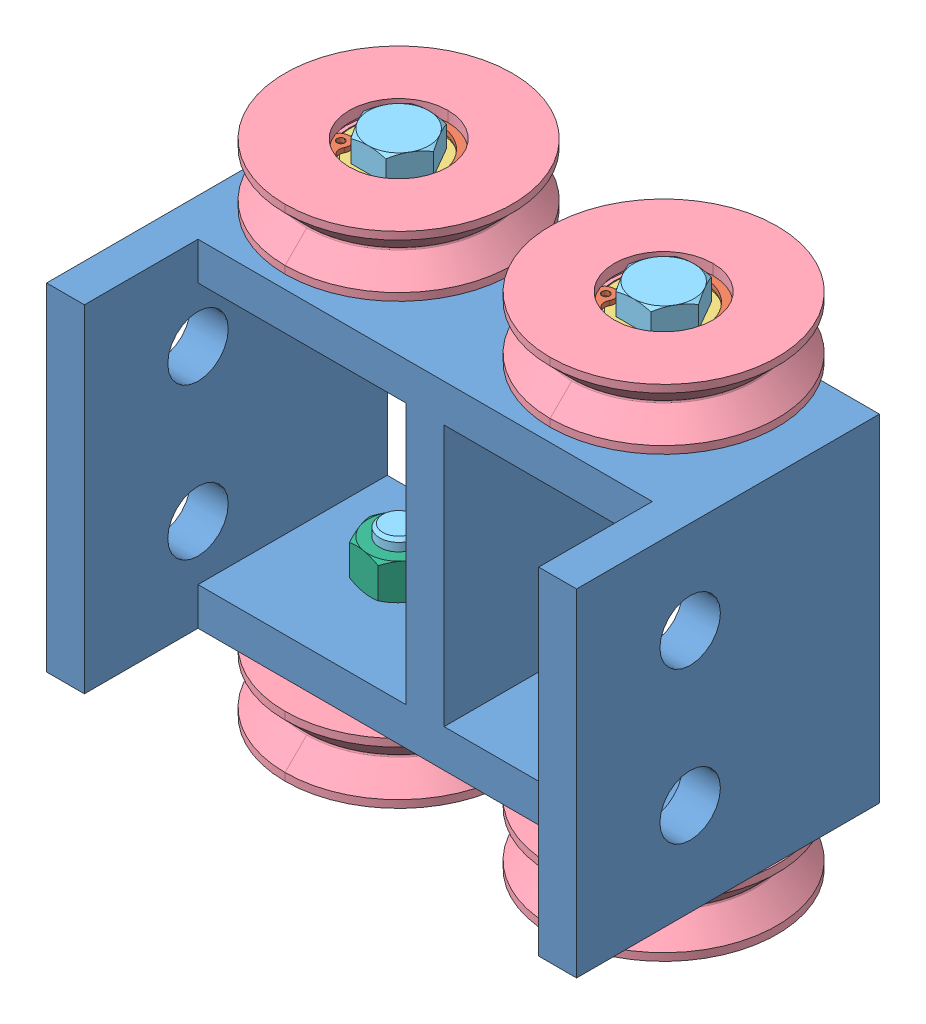
SolidWorks assembly Z_Hub, configuration Default. Lengths in mm.
Overall size (140 136.8 88).
29 component instances, 6 part files, 35 mates.
Components (placement in the parent):
- Z_Internal_Hub-1: Z_Internal_Hub [Default] at (36.1913 98.0055 130.8197) size (140 89 80)
- VMQN60_6-1: VMQN60_6 [Default] at (1.1913 39.5245 152.8197) x (0 1 0) z (0 0 1) size (16 60 60)
  - VMQN60_6_3-1: VMQN60_6_3 [Default] at (-4.6 0 0) size (1.2 26.01 27.2)
  - VMQN60_6_5-1: VMQN60_6_5 [Default] at (4 0 0) x (-1 0 0) z (0 0 1) size (8 26 26)
  - VMQN60_6_7-1: VMQN60_6_7 [Default] at origin size (16 60 60)
- VMQN60_6-2: VMQN60_6 [Default] at (71.1913 155.5245 152.8197) x (0 -1 0) z (0 0 1) size (16 60 60)
  - VMQN60_6_3-1: VMQN60_6_3 [Default] at (-4.6 0 0) size (1.2 26.01 27.2)
  - VMQN60_6_5-1: VMQN60_6_5 [Default] at (4 0 0) x (-1 0 0) z (0 0 1) size (8 26 26)
  - VMQN60_6_7-1: VMQN60_6_7 [Default] at origin size (16 60 60)
- VMQN60_6-3: VMQN60_6 [Default] at (1.1913 155.5245 152.8197) x (0 -1 0) z (0 0 1) size (16 60 60)
  - VMQN60_6_3-1: VMQN60_6_3 [Default] at (-4.6 0 0) size (1.2 26.01 27.2)
  - VMQN60_6_5-1: VMQN60_6_5 [Default] at (4 0 0) x (-1 0 0) z (0 0 1) size (8 26 26)
  - VMQN60_6_7-1: VMQN60_6_7 [Default] at origin size (16 60 60)
- VMQN60_6-4: VMQN60_6 [Default] at (71.1913 39.5245 152.8197) x (0 1 0) z (0 0 1) size (16 60 60)
  - VMQN60_6_3-1: VMQN60_6_3 [Default] at (-4.6 0 0) size (1.2 26.01 27.2)
  - VMQN60_6_5-1: VMQN60_6_5 [Default] at (4 0 0) x (-1 0 0) z (0 0 1) size (8 26 26)
  - VMQN60_6_7-1: VMQN60_6_7 [Default] at origin size (16 60 60)
- hex bolt gradeb_iso-1: hex bolt gradeb_iso [ISO 4015 - M10 x 40 x 40-N] at (71.1913 29.1245 152.8197) x (0 1 0) z (0 0 1) size (46.4 18.48 16)
- hex bolt gradeb_iso-2: hex bolt gradeb_iso [ISO 4015 - M10 x 40 x 40-N] at (1.1913 29.1245 152.8197) x (0 1 0) z (0 0 1) size (46.4 18.48 16)
- hex bolt gradeb_iso-3: hex bolt gradeb_iso [ISO 4015 - M10 x 40 x 40-N] at (71.1913 165.9245 152.8197) x (0 -1 0) z (0 0 1) size (46.4 18.48 16)
- hex bolt gradeb_iso-4: hex bolt gradeb_iso [ISO 4015 - M10 x 40 x 40-N] at (1.1913 165.9245 152.8197) x (0 -1 0) z (0 0 1) size (46.4 18.48 16)
- hex nut gradec_iso-1: hex nut gradec_iso [ISO - 4034 - M10 - N] at (71.1913 53.0245 152.8197) x (0 0 -1) z (0 1 0) size (16 18.48 9.5)
- hex nut gradec_iso-2: hex nut gradec_iso [ISO - 4034 - M10 - N] at (1.1913 72.5245 152.8197) x (0.935987 0 -0.352035) z (0 1 0) size (16 18.48 9.5)
- hex nut gradec_iso-3: hex nut gradec_iso [ISO - 4034 - M10 - N] at (1.1913 53.0245 152.8197) x (0 0 -1) z (0 1 0) size (16 18.48 9.5)
- hex nut gradec_iso-4: hex nut gradec_iso [ISO - 4034 - M10 - N] at (71.1913 72.5245 152.8197) x (1 0 0) z (0 1 0) size (16 18.48 9.5)
- hex nut gradec_iso-5: hex nut gradec_iso [ISO - 4034 - M10 - N] at (1.1913 142.0245 152.8197) x (1 0 0) z (0 -1 0) size (16 18.48 9.5)
- hex nut gradec_iso-6: hex nut gradec_iso [ISO - 4034 - M10 - N] at (71.1913 142.0245 152.8197) x (0 0 -1) z (0 -1 0) size (16 18.48 9.5)
- hex nut gradec_iso-7: hex nut gradec_iso [ISO - 4034 - M10 - N] at (1.1913 122.5245 152.8197) x (1 0 0) z (0 -1 0) size (16 18.48 9.5)
- hex nut gradec_iso-8: hex nut gradec_iso [ISO - 4034 - M10 - N] at (71.1913 122.5245 152.8197) x (1 0 0) z (0 -1 0) size (16 18.48 9.5)
Mates (geometry in assembly coordinates):
- Concentric1: concentric aligned: cylinder of VMQN60_6-1/VMQN60_6_5-1 through (1.1913 35.5245 152.8197) axis (0 -1 0) radius 5; cylinder of hex bolt gradeb_iso-2 through (1.1913 29.1245 152.8197) axis (0 -1 0) radius 5
- Coincident1: coincident anti-aligned: plane of VMQN60_6-1/VMQN60_6_5-1 through (6.4913 35.5245 152.8197) normal (0 -1 0); plane of hex bolt gradeb_iso-2 through (1.1913 35.5245 136.8197) normal (0 1 0)
- Concentric2: concentric anti-aligned: cylinder of hex bolt gradeb_iso-2 through (1.1913 29.1245 152.8197) axis (0 -1 0) radius 5; cylinder of hex nut gradec_iso-3 through (1.1913 43.5245 152.8197) axis (0 1 0) radius 4.25
- Coincident2: coincident anti-aligned: plane of VMQN60_6-1/VMQN60_6_5-1 through (8.1413 43.5245 152.8197) normal (0 1 0); plane of hex nut gradec_iso-3 through (-8.0463 43.5245 152.8197) normal (0 -1 0)
- Concentric3: concentric aligned: cylinder of Z_Internal_Hub-1 through (1.1913 142.0245 152.8197) axis (0 -1 0) radius 5; cylinder of hex bolt gradeb_iso-2 through (1.1913 29.1245 152.8197) axis (0 -1 0) radius 5
- Coincident3: coincident anti-aligned: plane of Z_Internal_Hub-1 through (-33.8087 53.0245 180.8197) normal (0 -1 0); plane of hex nut gradec_iso-3 through (-8.0463 53.0245 152.8197) normal (0 1 0)
- Concentric4: concentric anti-aligned: cylinder of hex bolt gradeb_iso-2 through (1.1913 29.1245 152.8197) axis (0 -1 0) radius 5; cylinder of hex nut gradec_iso-2 through (1.1913 63.0245 152.8197) axis (0 1 0) radius 4.25
- Coincident4: coincident anti-aligned: plane of Z_Internal_Hub-1 through (-23.8087 63.0245 180.8197) normal (0 1 0); plane of hex nut gradec_iso-2 through (-2.0607 63.0245 144.1735) normal (0 -1 0)
- Concentric5: concentric aligned: cylinder of VMQN60_6-3/VMQN60_6_5-1 through (1.1913 159.5245 152.8197) axis (0 1 0) radius 5; cylinder of hex bolt gradeb_iso-4 through (1.1913 165.9245 152.8197) axis (0 1 0) radius 5
- Coincident5: coincident anti-aligned: plane of VMQN60_6-3/VMQN60_6_5-1 through (-4.1087 159.5245 152.8197) normal (0 1 0); plane of hex bolt gradeb_iso-4 through (1.1913 159.5245 136.8197) normal (0 -1 0)
- Concentric6: concentric anti-aligned: cylinder of Z_Internal_Hub-1 through (1.1913 142.0245 152.8197) axis (0 -1 0) radius 5; cylinder of hex bolt gradeb_iso-4 through (1.1913 165.9245 152.8197) axis (0 1 0) radius 5
- Concentric7: concentric anti-aligned: cylinder of hex bolt gradeb_iso-4 through (1.1913 165.9245 152.8197) axis (0 1 0) radius 5; cylinder of hex nut gradec_iso-5 through (1.1913 151.5245 152.8197) axis (0 -1 0) radius 4.25
- Coincident6: coincident anti-aligned: plane of VMQN60_6-3/VMQN60_6_5-1 through (-5.7587 151.5245 152.8197) normal (0 -1 0); plane of hex nut gradec_iso-5 through (1.1913 151.5245 162.0573) normal (0 1 0)
- Coincident7: coincident anti-aligned: plane of Z_Internal_Hub-1 through (-33.8087 142.0245 180.8197) normal (0 1 0); plane of hex nut gradec_iso-5 through (1.1913 142.0245 162.0573) normal (0 -1 0)
- Concentric8: concentric anti-aligned: cylinder of hex bolt gradeb_iso-4 through (1.1913 165.9245 152.8197) axis (0 1 0) radius 5; cylinder of hex nut gradec_iso-7 through (1.1913 132.0245 152.8197) axis (0 -1 0) radius 4.25
- Coincident8: coincident anti-aligned: plane of Z_Internal_Hub-1 through (-23.8087 132.0245 180.8197) normal (0 -1 0); plane of hex nut gradec_iso-7 through (1.1913 132.0245 162.0573) normal (0 1 0)
- Concentric9: concentric aligned: cylinder of VMQN60_6-4/VMQN60_6_5-1 through (71.1913 35.5245 152.8197) axis (0 -1 0) radius 5; cylinder of hex bolt gradeb_iso-1 through (71.1913 29.1245 152.8197) axis (0 -1 0) radius 5
- Coincident9: coincident anti-aligned: plane of VMQN60_6-4/VMQN60_6_5-1 through (76.4913 35.5245 152.8197) normal (0 -1 0); plane of hex bolt gradeb_iso-1 through (71.1913 35.5245 136.8197) normal (0 1 0)
- Concentric10: concentric anti-aligned: cylinder of hex bolt gradeb_iso-1 through (71.1913 29.1245 152.8197) axis (0 -1 0) radius 5; cylinder of hex nut gradec_iso-1 through (71.1913 43.5245 152.8197) axis (0 1 0) radius 4.25
- Coincident10: coincident anti-aligned: plane of VMQN60_6-4/VMQN60_6_5-1 through (78.1413 43.5245 152.8197) normal (0 1 0); plane of hex nut gradec_iso-1 through (61.9537 43.5245 152.8197) normal (0 -1 0)
- Concentric11: concentric aligned: cylinder of Z_Internal_Hub-1 through (71.1913 142.0245 152.8197) axis (0 -1 0) radius 5; cylinder of hex bolt gradeb_iso-1 through (71.1913 29.1245 152.8197) axis (0 -1 0) radius 5
- Coincident11: coincident anti-aligned: plane of Z_Internal_Hub-1 through (-33.8087 53.0245 180.8197) normal (0 -1 0); plane of hex nut gradec_iso-1 through (61.9537 53.0245 152.8197) normal (0 1 0)
- Concentric12: concentric anti-aligned: cylinder of hex bolt gradeb_iso-1 through (71.1913 29.1245 152.8197) axis (0 -1 0) radius 5; cylinder of hex nut gradec_iso-4 through (71.1913 63.0245 152.8197) axis (0 1 0) radius 4.25
- Coincident12: coincident anti-aligned: plane of Z_Internal_Hub-1 through (41.1913 63.0245 180.8197) normal (0 1 0); plane of hex nut gradec_iso-4 through (71.1913 63.0245 143.5821) normal (0 -1 0)
- Concentric13: concentric aligned: cylinder of VMQN60_6-2/VMQN60_6_5-1 through (71.1913 159.5245 152.8197) axis (0 1 0) radius 5; cylinder of hex bolt gradeb_iso-3 through (71.1913 165.9245 152.8197) axis (0 1 0) radius 5
- Coincident13: coincident anti-aligned: plane of VMQN60_6-2/VMQN60_6_5-1 through (65.8913 159.5245 152.8197) normal (0 1 0); plane of hex bolt gradeb_iso-3 through (71.1913 159.5245 136.8197) normal (0 -1 0)
- Concentric14: concentric anti-aligned: cylinder of hex bolt gradeb_iso-3 through (71.1913 165.9245 152.8197) axis (0 1 0) radius 5; cylinder of hex nut gradec_iso-6 through (71.1913 151.5245 152.8197) axis (0 -1 0) radius 4.25
- Coincident14: coincident anti-aligned: plane of VMQN60_6-2/VMQN60_6_5-1 through (64.2413 151.5245 152.8197) normal (0 -1 0); plane of hex nut gradec_iso-6 through (80.4289 151.5245 152.8197) normal (0 1 0)
- Coincident15: coincident anti-aligned: plane of Z_Internal_Hub-1 through (-33.8087 142.0245 180.8197) normal (0 1 0); plane of hex nut gradec_iso-6 through (80.4289 142.0245 152.8197) normal (0 -1 0)
- Concentric15: concentric anti-aligned: cylinder of Z_Internal_Hub-1 through (71.1913 142.0245 152.8197) axis (0 -1 0) radius 5; cylinder of hex bolt gradeb_iso-3 through (71.1913 165.9245 152.8197) axis (0 1 0) radius 5
- Concentric16: concentric anti-aligned: cylinder of hex bolt gradeb_iso-3 through (71.1913 165.9245 152.8197) axis (0 1 0) radius 5; cylinder of hex nut gradec_iso-8 through (71.1913 132.0245 152.8197) axis (0 -1 0) radius 4.25
- Coincident16: coincident anti-aligned: plane of Z_Internal_Hub-1 through (41.1913 132.0245 180.8197) normal (0 -1 0); plane of hex nut gradec_iso-8 through (71.1913 132.0245 162.0573) normal (0 1 0)
- Concentric17: concentric aligned: cylinder of Z_Internal_Hub-1 through (-18.8087 117.5245 180.8197) axis (-1 0 0) radius 8; cylinder of hex structural bolt gradec short_iso-1 through (-78.8087 112.0245 155.8197) axis (-1 0 0) radius 8
- Distance1: distance = 15 mm anti-aligned: plane of Z_Internal_Hub-1 through (-33.8087 142.0245 180.8197) normal (-1 0 0); plane of hex structural bolt gradec short_iso-1 through (-68.8087 127.613 155.8197) normal (1 0 0)
- Concentric18: concentric anti-aligned: cylinder of hex structural bolt gradec short_iso-1 through (-78.8087 112.0245 155.8197) axis (-1 0 0) radius 8; cylinder of hex nut gradec_iso-9 through (-36.1769 112.0245 155.8197) axis (1 0 0) radius 7
